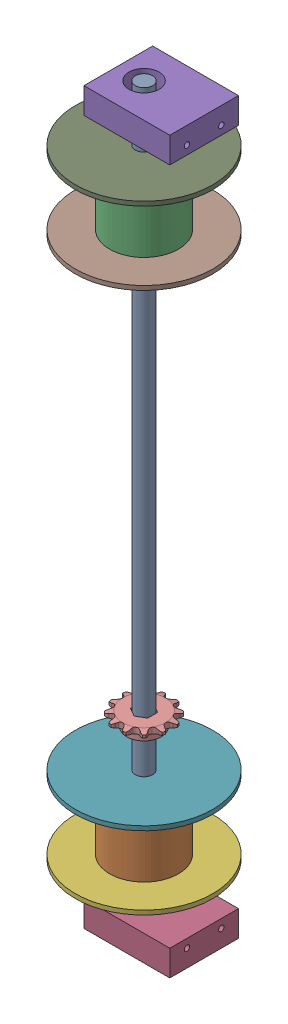
SolidWorks assembly Winding_Drum_Assy, configuration Default. Lengths in mm.
Overall size (101.6 539.75 101.6).
10 component instances, 5 part files, 0 mates.
Components (placement in the parent):
- winding_axle-1: winding_axle [Default] at (44.45 419.1 25.4) x (0 -1 0) z (0 0 1) size (539.75 12.7 12.7)
- winding drum-1: winding drum [Default] at (44.45 -25.4 25.4) x (0 -1 0) z (0 0 1) size (50.8 50.8 50.8)
- winding drum-2: winding drum [Default] at (44.45 374.65 25.4) x (0 -1 0) z (0 0 1) size (50.8 50.8 50.8)
- Bearing_block_End-1: Bearing_block_End [Default] at (88.9 -101.6 0) x (-1 0 0) z (0 0 1) size (63.5 19.05 50.8)
- Bearing_block_End-2: Bearing_block_End [Default] at (88.9 400.05 50.8) x (-1 0 0) z (0 0 -1) size (63.5 19.05 50.8)
- Drum_end_cap-1: Drum_end_cap [Default] at (44.45 -76.2 25.4) x (1 0 0) z (0 -1 0) size (101.6 101.6 3.17)
- Drum_end_cap-2: Drum_end_cap [Default] at (44.45 -22.225 25.4) x (1 0 0) z (0 -1 0) size (101.6 101.6 3.17)
- Drum_end_cap-3: Drum_end_cap [Default] at (44.45 323.85 25.4) x (1 0 0) z (0 -1 0) size (101.6 101.6 3.17)
- Drum_end_cap-4: Drum_end_cap [Default] at (44.45 377.825 25.4) x (1 0 0) z (0 -1 0) size (101.6 101.6 3.17)
- 217-2662.20121204.1-1: 217-2662.20121204.1 [Default] at (44.45 13.7287 25.4) x (1 0 0) z (0 -1 0) size (40.29 40.29 10.67)
